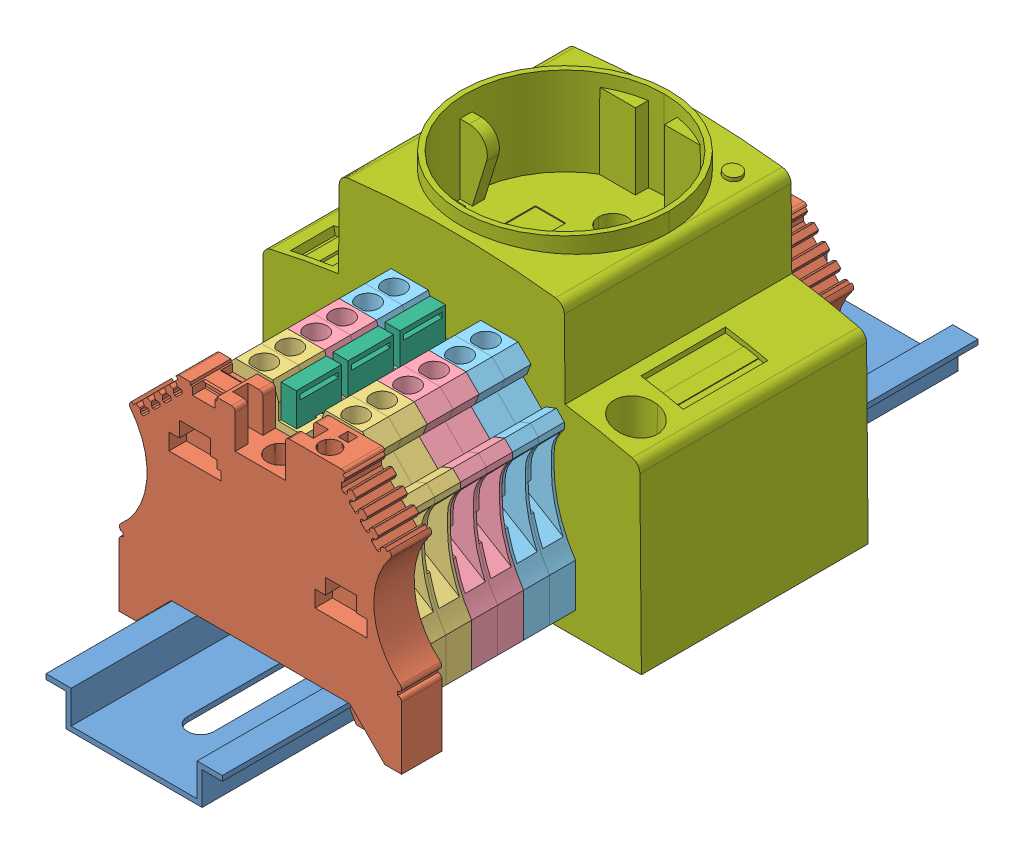
SolidWorks assembly Baugruppe1, configuration Standard. Lengths in mm.
Overall size (75.48 67.56 150).
13 component instances, 7 part files, 39 mates.
Components (placement in the parent):
- Hutschiene-1: Hutschiene [150] at (-17.5 -7.5 -150) size (35 7.5 150)
- WEW_35_2-1: WEW_35_2 [Standard] at (-45.49 -7 -33) x (0 0 1) z (0 1 0) size (8 56.1 46.5)
- UT_2.5-1: UT_2.5 [Standard] at (-48.9989 10.6178 -38.15) x (0.992546 -0.121869 0) z (0 0 1) size (49.27 50.96 5.15)
- UT_2.5-2: UT_2.5 [Standard] at (-48.9989 10.6178 -33) x (0.992546 -0.121869 0) z (0 0 1) size (49.27 50.96 5.15)
- UT_2.5_BU-1: UT_2.5_BU [Standard] at (-48.9989 10.6178 -43.3) x (0.992546 -0.121869 0) z (0 0 1) size (49.27 50.96 5.15)
- UT_2.5_BU-2: UT_2.5_BU [Standard] at (-48.9989 10.6178 -48.45) x (0.992546 -0.121869 0) z (0 0 1) size (49.27 50.96 5.15)
- UT_2.5_PE-1: UT_2.5_PE [Standard] at (-48.9989 10.6178 -53.6) x (0.992546 -0.121869 0) z (0 0 1) size (49.27 50.96 5.15)
- UT_2.5_PE-2: UT_2.5_PE [Standard] at (-48.9989 10.6178 -58.75) x (0.992546 -0.121869 0) z (0 0 1) size (49.27 50.96 5.15)
- FBS_2-5-1: FBS_2-5 [Standard] at (-24.4072 49.175 -91.835) size (3 22.98 9)
- FBS_2-5-3: FBS_2-5 [Standard] at (-24.4072 49.175 -102.135) size (3 22.98 9)
- FBS_2-5-2: FBS_2-5 [Standard] at (-24.4072 49.175 -112.435) size (3 22.98 9)
- EO_CF_UT_LED-1: EO_CF_UT_LED [Standard] at (-87.6914 -21.0563 -88.65) size (75.48 61.64 45)
- WEW_35_2-2: WEW_35_2 [Standard] at (-45.61 -7 -116.9) x (0 0 1) z (0 1 0) size (8 56.1 46.5)
Mates (geometry in assembly coordinates):
- Deckungsgleich1: coincident aligned: plane of Hutschiene-1 through (-17.5 -7.5 0) normal (0 0 1); plane of assembly through (0 0 0) normal (0 0 1)
- Deckungsgleich2: coincident aligned: plane of Hutschiene-1 through (0 -1 0) normal (1 0 0); plane of assembly through (0 0 0) normal (1 0 0)
- Deckungsgleich3: coincident aligned: plane of Hutschiene-1 through (0 0 0) normal (0 1 0); plane of assembly through (0 0 0) normal (0 1 0)
- Deckungsgleich4: coincident anti-aligned: plane of Hutschiene-1 through (-30 0 0) normal (0 1 0); plane of WEW_35_2-1 through (0.26 0 -25) normal (0 -1 0)
- Tangential1: tangent anti-aligned: cylinder of WEW_35_2-1 through (-37 -1.4 -29) axis (0 0 1) radius 2; plane of Hutschiene-1 through (-35 0 0) normal (-1 0 0)
- Abstand1: distance = 25 mm aligned: plane of Hutschiene-1 through (-17.5 -7.5 0) normal (0 0 1); plane of WEW_35_2-1 through (-17.44 0 -25) normal (0 0 1)
- Deckungsgleich6: coincident anti-aligned: plane of UT_2.5-2 through (-0.3 0 -33) normal (0 0 1); plane of WEW_35_2-1 through (-17.44 0 -33) normal (0 0 -1)
- Deckungsgleich7: coincident anti-aligned: plane of UT_2.5-1 through (-0.3 0 -38.15) normal (0 0 1); plane of UT_2.5-2 through (-0.3 0 -38.15) normal (0 0 -1)
- Deckungsgleich8: coincident anti-aligned: plane of UT_2.5-1 through (-0.3 0 -43.3) normal (0 0 -1); plane of UT_2.5_BU-1 through (-0.3 0 -43.3) normal (0 0 1)
- Deckungsgleich9: coincident anti-aligned: plane of UT_2.5_BU-1 through (-0.3 0 -48.45) normal (0 0 -1); plane of UT_2.5_BU-2 through (-0.3 0 -48.45) normal (0 0 1)
- Deckungsgleich10: coincident anti-aligned: plane of UT_2.5_BU-2 through (-0.3 0 -53.6) normal (0 0 -1); plane of UT_2.5_PE-1 through (-0.3 0 -53.6) normal (0 0 1)
- Deckungsgleich11: coincident anti-aligned: plane of UT_2.5_PE-1 through (-0.3 0 -58.75) normal (0 0 -1); plane of UT_2.5_PE-2 through (-0.3 0 -58.75) normal (0 0 1)
- Deckungsgleich12: coincident anti-aligned: plane of UT_2.5_PE-2 through (-0.3 0 -63.9) normal (0 0 -1); plane of EO_CF_UT_LED-1 through (-18.35 2.45 -63.9) normal (0 0 1)
- Deckungsgleich13: coincident anti-aligned: plane of UT_2.5-2 through (-21.8 36.703 -33) normal (1 0 0); plane of FBS_2-5-1 through (-21.8 41.9423 -67.735) normal (-1 0 0)
- Deckungsgleich14: coincident anti-aligned: plane of UT_2.5-2 through (-18.65 21.85 -33.475) normal (0 0 -1); plane of FBS_2-5-1 through (-18.8 39.7 -33.475) normal (0 0 1)
- Deckungsgleich15: coincident aligned: plane of UT_2.5-2 through (-30.4 40 -33) normal (0 1 0); plane of FBS_2-5-1 through (-18.8 40 -12.975) normal (0 1 0)
- Deckungsgleich16: coincident anti-aligned: plane of UT_2.5_BU-1 through (-21.8 36.703 -43.3) normal (1 0 0); plane of FBS_2-5-3 through (-21.8 41.9423 -78.035) normal (-1 0 0)
- Deckungsgleich17: coincident anti-aligned: plane of UT_2.5_BU-1 through (-18.65 21.85 -43.775) normal (0 0 -1); plane of FBS_2-5-3 through (-18.8 39.7 -43.775) normal (0 0 1)
- Deckungsgleich18: coincident aligned: plane of UT_2.5_BU-1 through (-30.4 40 -43.3) normal (0 1 0); plane of FBS_2-5-3 through (-18.8 40 -23.275) normal (0 1 0)
- Deckungsgleich19: coincident anti-aligned: plane of UT_2.5_PE-1 through (-18.65 21.85 -54.075) normal (0 0 -1); plane of FBS_2-5-2 through (-18.8 39.7 -54.075) normal (0 0 1)
- Deckungsgleich20: coincident anti-aligned: plane of UT_2.5_PE-1 through (-21.8 36.703 -53.6) normal (1 0 0); plane of FBS_2-5-2 through (-21.8 41.9423 -88.335) normal (-1 0 0)
- Deckungsgleich21: coincident aligned: plane of UT_2.5_PE-1 through (-30.4 40 -53.6) normal (0 1 0); plane of FBS_2-5-2 through (-18.8 40 -33.575) normal (0 1 0)
- Deckungsgleich22: coincident anti-aligned: plane of Hutschiene-1 through (0 0 0) normal (0 1 0); plane of WEW_35_2-2 through (0.14 0 -108.9) normal (0 -1 0)
- Deckungsgleich23: coincident anti-aligned: plane of EO_CF_UT_LED-1 through (-18.35 2.45 -108.9) normal (0 0 -1); plane of WEW_35_2-2 through (-17.56 0 -108.9) normal (0 0 1)
- Tangential2: tangent anti-aligned: plane of Hutschiene-1 through (0 -1 0) normal (1 0 0); cylinder of WEW_35_2-2 through (2 -1.4 -112.9) axis (0 0 1) radius 2
- Deckungsgleich24: coincident anti-aligned: plane of Hutschiene-1 through (0 0 0) normal (0 1 0); plane of UT_2.5-2 through (-8 0 -33) normal (0 -1 0)
- Deckungsgleich25: coincident anti-aligned: plane of Hutschiene-1 through (-30 0 0) normal (0 1 0); plane of UT_2.5-1 through (-8 0 -38.15) normal (0 -1 0)
- Deckungsgleich26: coincident anti-aligned: plane of Hutschiene-1 through (-30 0 0) normal (0 1 0); plane of UT_2.5_BU-1 through (-8 0 -43.3) normal (0 -1 0)
- Deckungsgleich27: coincident anti-aligned: plane of Hutschiene-1 through (-30 0 0) normal (0 1 0); plane of UT_2.5_BU-2 through (-8 0 -48.45) normal (0 -1 0)
- Deckungsgleich28: coincident anti-aligned: plane of Hutschiene-1 through (-30 0 0) normal (0 1 0); plane of UT_2.5_PE-1 through (-8 0 -53.6) normal (0 -1 0)
- Deckungsgleich29: coincident anti-aligned: plane of Hutschiene-1 through (-30 0 0) normal (0 1 0); plane of UT_2.5_PE-2 through (-8 0 -58.75) normal (0 -1 0)
- Deckungsgleich30: coincident anti-aligned: plane of Hutschiene-1 through (0 0 0) normal (0 1 0); plane of EO_CF_UT_LED-1 through (-54.65 0 -90.8) normal (0 -1 0)
- Deckungsgleich31: coincident anti-aligned: plane of Hutschiene-1 through (-35 0 0) normal (-1 0 0); plane of UT_2.5-2 through (-35 -0.3 -33) normal (1 0 0)
- Deckungsgleich32: coincident anti-aligned: plane of Hutschiene-1 through (-35 0 0) normal (-1 0 0); plane of UT_2.5-1 through (-35 -0.3 -38.15) normal (1 0 0)
- Deckungsgleich33: coincident anti-aligned: plane of Hutschiene-1 through (-35 0 0) normal (-1 0 0); plane of UT_2.5_BU-1 through (-35 -0.3 -43.3) normal (1 0 0)
- Deckungsgleich34: coincident anti-aligned: plane of Hutschiene-1 through (-35 0 0) normal (-1 0 0); plane of UT_2.5_BU-2 through (-35 -0.3 -48.45) normal (1 0 0)
- Deckungsgleich35: coincident anti-aligned: plane of Hutschiene-1 through (-35 0 0) normal (-1 0 0); plane of UT_2.5_PE-1 through (-35 -0.3 -53.6) normal (1 0 0)
- Deckungsgleich36: coincident anti-aligned: plane of Hutschiene-1 through (-35 0 0) normal (-1 0 0); plane of UT_2.5_PE-2 through (-35 -0.3 -58.75) normal (1 0 0)
- Deckungsgleich37: coincident anti-aligned: plane of Hutschiene-1 through (-35 0 0) normal (-1 0 0); plane of EO_CF_UT_LED-1 through (-35 -41.451 -95.15) normal (1 0 0)
